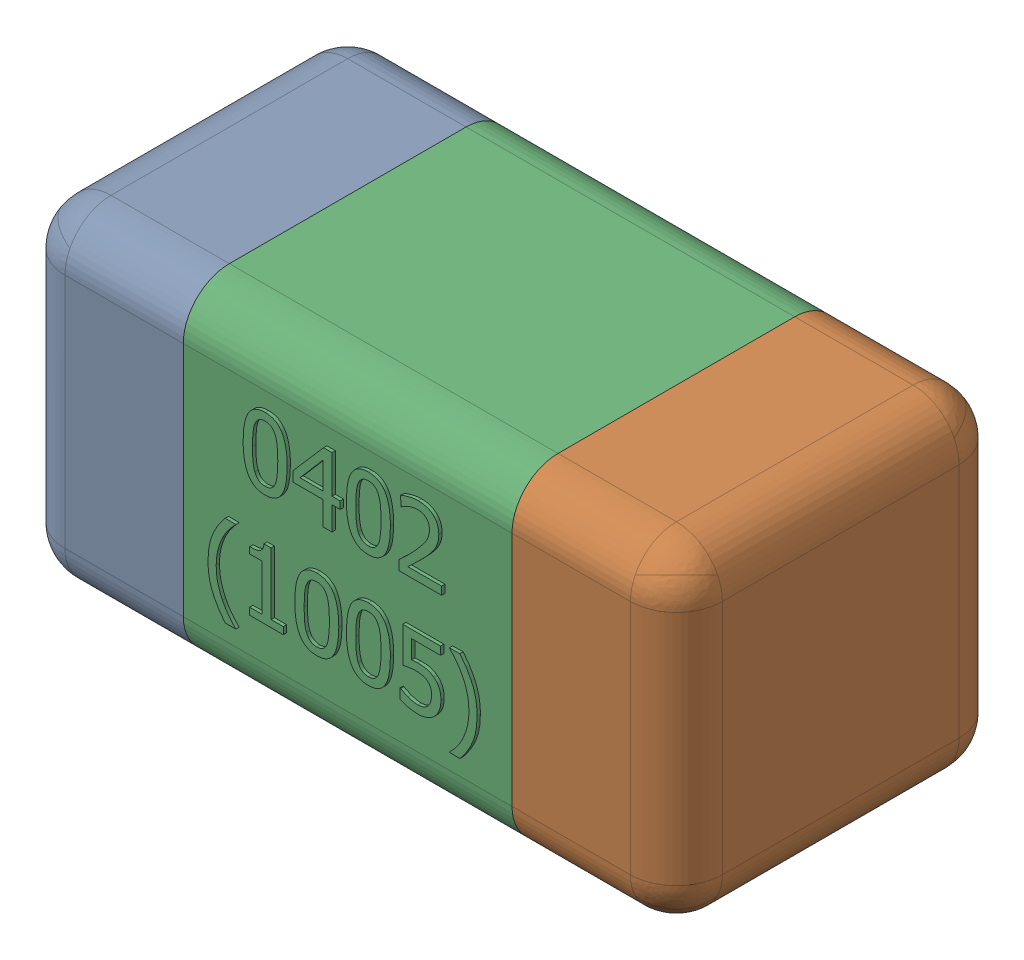
SolidWorks assembly C10, configuration Standard. Lengths in mm.
Overall size (1.01 0.51 0.51).
4 component instances, 3 part files, 0 mates.
Components (placement in the parent):
- C10-subassembly-1-1: C10-subassembly-1 [Standard] at (-2.9999 7 0) x (1 0 0) z (0 0 1) size (1.01 0.51 0.51)
  - User Library-0402_Cap-1: User Library-0402_Cap [Standard] at origin size (0.26 0.51 0.51)
  - User Library-0402_Cap-1-1: User Library-0402_Cap-1 [Standard] at origin size (0.26 0.5 0.51)
  - User Library-0402_Cap-2-1: User Library-0402_Cap-2 [Standard] at origin size (0.5 0.5 0.51)
